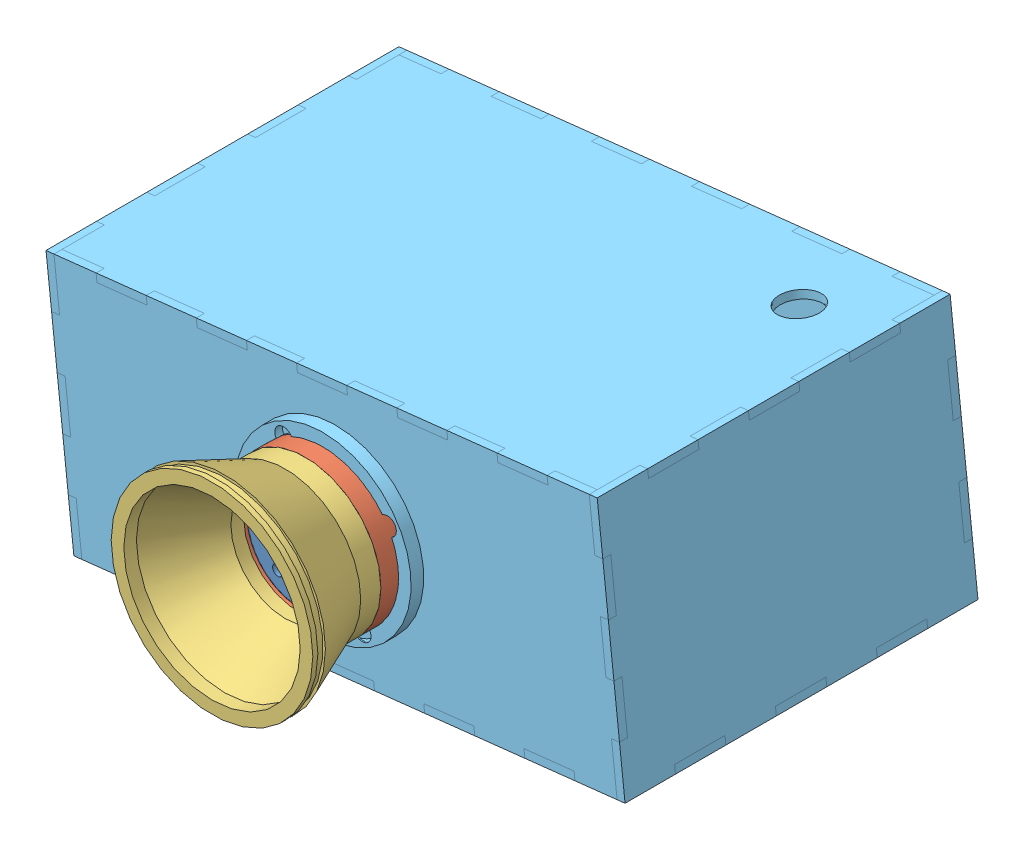
SolidWorks assembly FED_Operant, configuration Default. Lengths in mm.
Overall size (229.7 123.7 189).
8 component instances, 8 part files, 21 mates.
Components (placement in the parent):
- 20mg feeding disk-2: 20mg feeding disk [Default] at (-0.0232 -0.0039 16.5234) x (0.165238 -0.986254 0) z (0 0 -1) size (43.5 43.5 8)
- Motor mount-1: Motor mount [Default] at (0 0 -13) x (-0.9889 -0.14858 0) z (0 0 1) size (67 67 13)
- Food silo-2: Food silo [Default] at (0 0 -3) size (80 80 37)
- motor outline-1: motor outline [Default] at (-1.3623 7.8833 -33.25) x (-0.986254 -0.165238 0) z (-0.165238 0.986254 0) size (28 30 28)
- Base_top-1: Base_top [Default] at (0 0.0001 -753.1019) x (-0.993873 -0.110526 0) z (0 0 1) size (220 100 145)
- funnel-1: funnel [Default] at (5.3712 -44.68 -99.6) x (0.993873 0.110526 0) z (0.110526 -0.993873 0) size (80.8 69.3 38)
- photoInterruptor_outline-1: photoInterruptor_outline [Default] at (4.8186 -39.7106 -128.2) x (-0.993873 -0.110526 0) z (-0.110526 0.993873 0) size (18.6 15.2 5)
- front plate V1.2-1: front plate V1.2 [Default] at (5.9238 -49.6494 -99.6) x (0.993873 0.110526 0) z (0.110526 -0.993873 0) size (60.8 59.3 10)
Mates (geometry in assembly coordinates):
- Coincident2: coincident: plane of 20mg feeding disk-2 through (0 0 -3) normal (0 0 -1); plane of Motor mount-1 through (0 0 -3) normal (0 0 1)
- Concentric3: concentric: cylinder of 20mg feeding disk-2 through (0 0 -9) axis (0 0 1) radius 7; cylinder of Motor mount-1 through (0 0 -3) axis (0 0 -1) radius 8
- Coincident5: coincident: plane of Motor mount-1 through (0 0 0) normal (0 0 1); plane of Food silo-2 through (0 0 0) normal (0 0 -1)
- Concentric5: concentric: circle of Motor mount-1; circle of Food silo-2
- Coincident11: coordinate: point of Food silo-2; point of assembly
- Coincident39: coincident: plane of 20mg feeding disk-2 through (0.0404 0.0068 -3.25) normal (0 0 -1); plane of motor outline-1 through (-0.0404 -0.0068 -3.25) normal (0 0 1)
- Concentric28: concentric: circle of 20mg feeding disk-2; circle of motor outline-1
- Parallel1: parallel: line of 20mg feeding disk-2 through (2.4052 -1.2447 -3.25) axis (-0.986254 -0.165238 0); line of motor outline-1 through (-2.2607 1.1421 -9.25) axis (0.986254 0.165238 0)
- Coincident57: coincident: plane of Motor mount-1 through (0 0 -13) normal (0 0 -1); plane of Base_top-1 through (-15.606 25.6214 -13) normal (0 0 1)
- Coincident66: coincident: plane of Base_top-1 through (35.7866 -43.1338 -68.2) normal (-0.993873 -0.110526 0); plane of front plate V1.2-1 through (35.5849 -41.32 -68.2) normal (0.993873 0.110526 0)
- Coincident79: coincident: plane of funnel-1 through (5.3712 -44.68 -99.6) normal (0.110526 -0.993873 0); plane of photoInterruptor_outline-1 through (5.3712 -44.68 -128.2) normal (0.110526 -0.993873 0)
- Coincident80: coincident: plane of Base_top-1 through (-24.6408 -49.8538 -68.2) normal (0 0 -1); plane of front plate V1.2-1 through (-24.8426 -48.04 -68.2) normal (0 0 1)
- Coincident81: coincident: plane of front plate V1.2-1 through (-24.8426 -48.04 -68.2) normal (0 0 1); plane of funnel-1 through (-25.1741 -45.0584 -68.2) normal (0 0 -1)
- Coincident82: coincident: plane of front plate V1.2-1 through (5.3712 -44.68 -99.6) normal (-0.110526 0.993873 0); plane of funnel-1 through (5.3712 -44.68 -99.6) normal (0.110526 -0.993873 0)
- Coincident83: coincident: plane of front plate V1.2-1 through (35.5849 -41.32 -68.2) normal (0.993873 0.110526 0); plane of funnel-1 through (35.2534 -38.3384 -126) normal (-0.993873 -0.110526 0)
- Coincident84: coincident: plane of Base_top-1 through (5.5263 -49.6936 -753.1019) normal (0.110526 -0.993873 0); plane of front plate V1.2-1 through (5.9238 -49.6494 -99.6) normal (0.110526 -0.993873 0)
- Coincident85: coincident: plane of funnel-1 through (14.0616 -38.6827 -116) normal (0 0 -1); plane of photoInterruptor_outline-1 through (10.3406 -44.1274 -116) normal (0 0 1)
- Coincident86: coincident: plane of funnel-1 through (5.3712 -44.68 -99.6) normal (0.110526 -0.993873 0); plane of front plate V1.2-1 through (5.3712 -44.68 -99.6) normal (-0.110526 0.993873 0)
- Coincident88: coincident: plane of Base_top-1 through (5.5263 -49.6936 -753.1019) normal (0.110526 -0.993873 0); plane of front plate V1.2-1 through (5.9238 -49.6494 -99.6) normal (0.110526 -0.993873 0)
- Coincident89: coincident: plane of Base_top-1 through (35.7866 -43.1338 -68.2) normal (-0.993873 -0.110526 0); plane of front plate V1.2-1 through (35.5849 -41.32 -68.2) normal (0.993873 0.110526 0)
- Coincident90: coincident: plane of Base_top-1 through (-24.6408 -49.8538 -68.2) normal (0 0 -1); plane of front plate V1.2-1 through (-24.8426 -48.04 -68.2) normal (0 0 1)
